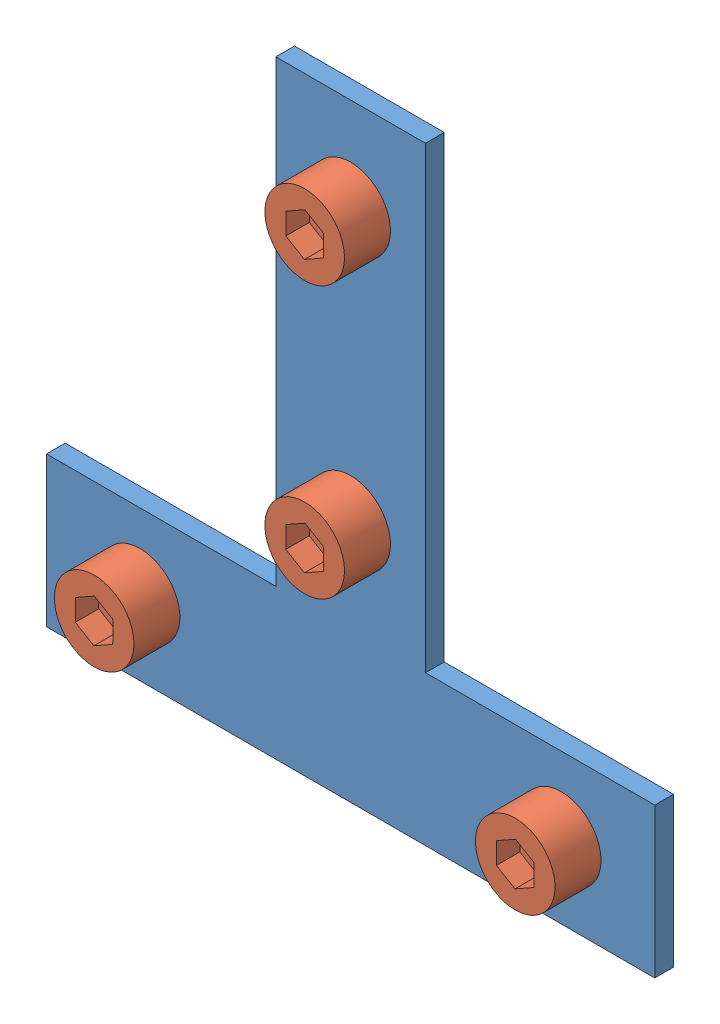
SolidWorks assembly T形连接片2020加螺丝, configuration 默认. Lengths in mm.
Overall size (65 65 12.01).
9 component instances, 3 part files, 16 mates.
Components (placement in the parent):
- T形连接片2020-1: T形连接片2020 [默认] at (-53.4474 -33.9962 64) x (1 0 0) z (0 -1 0) size (65 2 65)
- M5_6-1: M5_6 [默认] at (-20.9474 21.0038 60) x (1 0 0) z (0 -1 0) size (8.5 10.91 8.5)
- M5_6-2: M5_6 [默认] at (-20.9474 -7.9962 60) x (1 0 0) z (0 -1 0) size (8.5 10.91 8.5)
- M5_6-3: M5_6 [默认] at (-43.4474 -25.9962 60) x (1 0 0) z (0 -1 0) size (8.5 10.91 8.5)
- M5_6-4: M5_6 [默认] at (1.5526 -25.9962 60) x (1 0 0) z (0 -1 0) size (8.5 10.91 8.5)
- 欧标20M5滑块螺母-1: 欧标20M5滑块螺母 [默认] at (-16.1974 16.2538 58.9) x (0 1 0) z (1 0 0) size (9.5 4.5 9.5)
- 欧标20M5滑块螺母-2: 欧标20M5滑块螺母 [默认] at (-25.6974 -3.2462 58.9) x (0 -1 0) z (-1 0 0) size (9.5 4.5 9.5)
- 欧标20M5滑块螺母-3: 欧标20M5滑块螺母 [默认] at (-3.1974 -30.7462 58.9) x (1 0 0) z (0 -1 0) size (9.5 4.5 9.5)
- 欧标20M5滑块螺母-4: 欧标20M5滑块螺母 [默认] at (-48.1974 -30.7462 58.9) x (1 0 0) z (0 -1 0) size (9.5 4.5 9.5)
Mates (geometry in assembly coordinates):
- 重合2: coincident: plane of assembly; plane of assembly; plane of T形连接片2020-1 through (-53.4474 -33.9962 66) normal (0 0 1); plane of M5_6-1 through (-20.9474 21.0038 66) normal (0 0 -1)
- 重合3: coincident: plane of assembly; plane of assembly; plane of T形连接片2020-1 through (-53.4474 -33.9962 66) normal (0 0 1); plane of M5_6-2 through (-20.9474 -7.9962 66) normal (0 0 -1)
- 重合4: coincident: plane of assembly; plane of assembly; plane of T形连接片2020-1 through (-53.4474 -33.9962 66) normal (0 0 1); plane of M5_6-4 through (1.5526 -25.9962 66) normal (0 0 -1)
- 重合5: coincident: plane of assembly; plane of assembly; plane of T形连接片2020-1 through (-53.4474 -33.9962 66) normal (0 0 1); plane of M5_6-3 through (-43.4474 -25.9962 66) normal (0 0 -1)
- 同心1: concentric: cylinder of assembly; cylinder of assembly; cylinder of T形连接片2020-1 through (-43.4474 -25.9962 66) axis (0 0 -1) radius 2.75; cylinder of M5_6-3 through (-43.4474 -25.9962 66) axis (0 0 -1) radius 2.5
- 同心2: concentric: cylinder of assembly; cylinder of assembly; cylinder of T形连接片2020-1 through (1.5526 -25.9962 66) axis (0 0 -1) radius 2.75; cylinder of M5_6-4 through (1.5526 -25.9962 66) axis (0 0 -1) radius 2.5
- 同心3: concentric: cylinder of assembly; cylinder of assembly; cylinder of T形连接片2020-1 through (-20.9474 -7.9962 66) axis (0 0 -1) radius 2.75; cylinder of M5_6-2 through (-20.9474 -7.9962 66) axis (0 0 -1) radius 2.5
- 同心4: concentric: cylinder of assembly; cylinder of assembly; cylinder of T形连接片2020-1 through (-20.9474 21.0038 66) axis (0 0 -1) radius 2.75; cylinder of M5_6-1 through (-20.9474 21.0038 66) axis (0 0 -1) radius 2.5
- 同心5: concentric: cylinder of assembly; cylinder of assembly; cylinder of M5_6-1 through (-20.9474 21.0038 66) axis (0 0 -1) radius 2.5; cylinder of 欧标20M5滑块螺母-1 through (-20.9474 21.0038 58.9) axis (0 0 1) radius 2.5
- 同心6: concentric: cylinder of assembly; cylinder of assembly; cylinder of M5_6-2 through (-20.9474 -7.9962 66) axis (0 0 -1) radius 2.5; cylinder of 欧标20M5滑块螺母-2 through (-20.9474 -7.9962 58.9) axis (0 0 1) radius 2.5
- 同心7: concentric: cylinder of assembly; cylinder of assembly; cylinder of M5_6-4 through (1.5526 -25.9962 66) axis (0 0 -1) radius 2.5; cylinder of 欧标20M5滑块螺母-3 through (1.5526 -25.9962 58.9) axis (0 0 1) radius 2.5
- 同心8: concentric: cylinder of assembly; cylinder of assembly; cylinder of M5_6-3 through (-43.4474 -25.9962 66) axis (0 0 -1) radius 2.5; cylinder of 欧标20M5滑块螺母-4 through (-43.4474 -25.9962 58.9) axis (0 0 1) radius 2.5
- 距离1: distance = 1.8 mm: plane of assembly; plane of assembly; plane of 欧标20M5滑块螺母-1 through (-16.1974 16.2538 62.2) normal (0 0 1); plane of T形连接片2020-1 through (-53.4474 -33.9962 64) normal (0 0 -1)
- 距离2: distance = 1.8 mm: plane of assembly; plane of assembly; plane of 欧标20M5滑块螺母-2 through (-25.6974 -3.2462 62.2) normal (0 0 1); plane of T形连接片2020-1 through (-53.4474 -33.9962 64) normal (0 0 -1)
- 距离3: distance = 1.8 mm: plane of assembly; plane of assembly; plane of T形连接片2020-1 through (-53.4474 -33.9962 64) normal (0 0 -1); plane of 欧标20M5滑块螺母-3 through (-3.1974 -30.7462 62.2) normal (0 0 1)
- 距离4: distance = 1.8 mm: plane of assembly; plane of assembly; plane of T形连接片2020-1 through (-53.4474 -33.9962 64) normal (0 0 -1); plane of 欧标20M5滑块螺母-4 through (-48.1974 -30.7462 62.2) normal (0 0 1)
